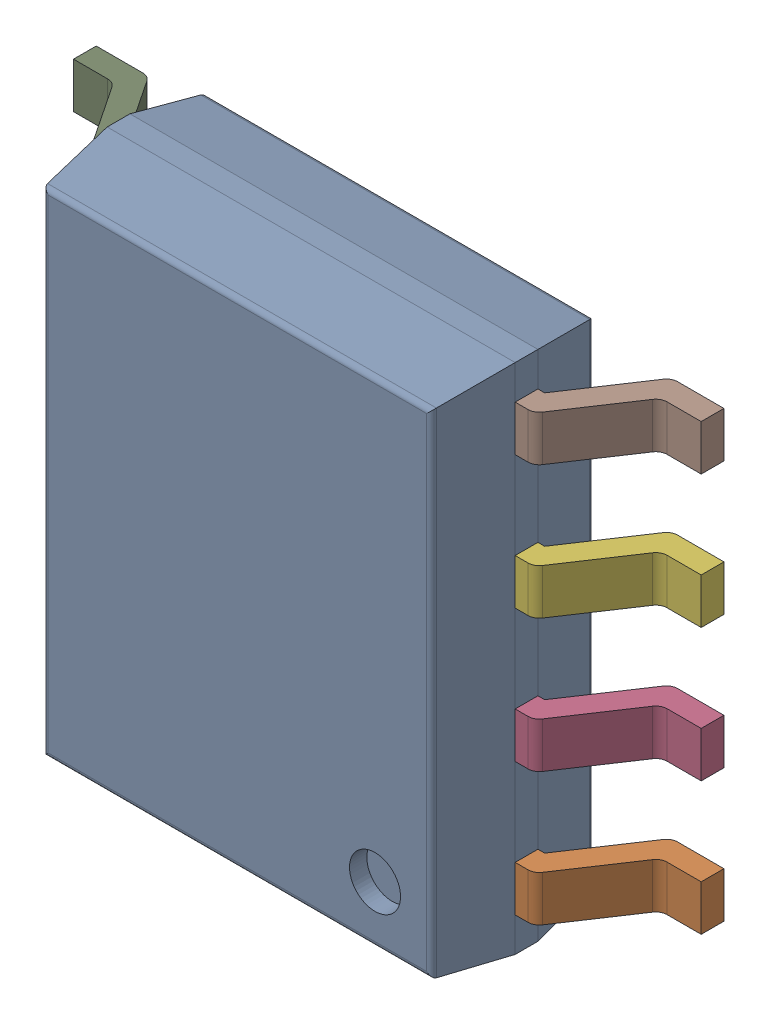
SolidWorks assembly IC23_1.step, configuration Default. Lengths in mm.
Overall size (6 4.9 1.65).
4 component instances, 3 part files, 0 mates.
Components (placement in the parent):
- 6348795168_1.step-11: 6348795168_1.step [Default] at (530.978 330.454 0) x (-1 0 0) z (0 0 1) size (6 4.9 1.65)
  - Body-6_1.step-11: Body-6_1.step [Default] at origin size (3.9 4.9 1.55)
  - PinsArrayLR_1.step-11: PinsArrayLR_1.step [Default] at origin size (6 4.24 0.95)
  - ThermalPad_1.step-11: ThermalPad_1.step [Default] at (-1.045 -1.045 0) size (2.09 2.09 0.1)
